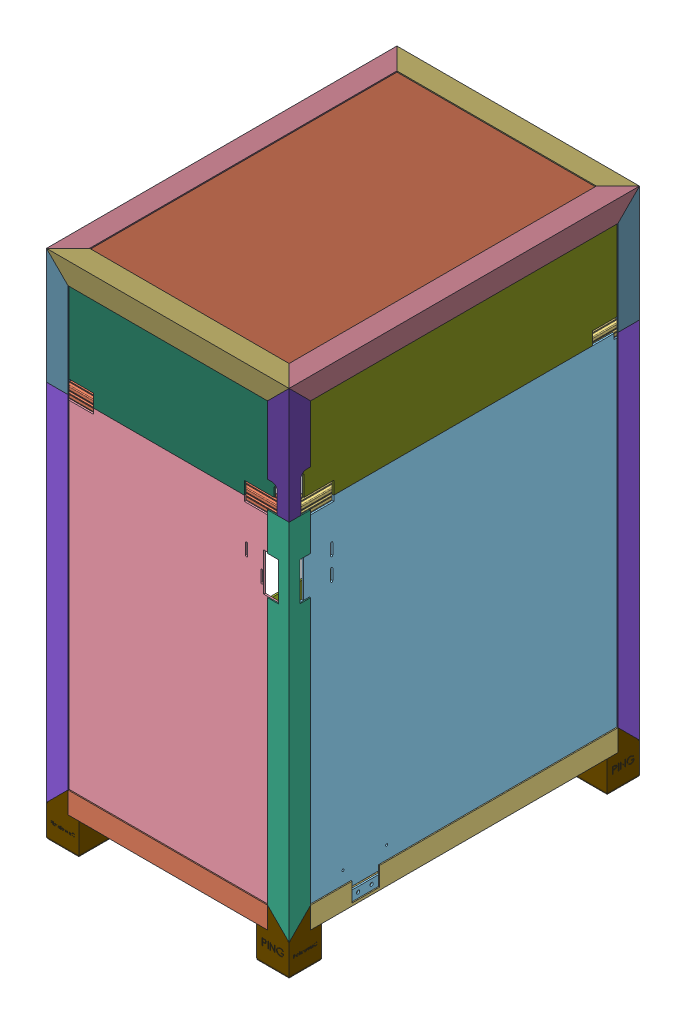
SolidWorks assembly carcasse, configuration Défaut. Lengths in mm.
Overall size (450 950 650).
53 component instances, 24 part files, 67 mates.
Components (placement in the parent):
- cadre-1: cadre [Défaut] at (-215.194 -19.8636 -400) size (440 20 640)
  - Blocks-1: Blocks [Défaut] at (-153.6103 82.5412 1245.1575) x (0 1 0) z (0 0 1) size (20 20 20)
  - Blocks-3: Blocks [Défaut] at (-153.6103 62.5412 625.1575) x (0 0 -1) z (0 1 0) size (20 20 20)
  - Blocks-4: Blocks [Défaut] at (246.3897 82.5412 645.1575) x (0 1 0) z (0 0 -1) size (20 20 20)
  - Blocks-5: Blocks [Défaut] at (246.3897 62.5412 1265.1575) x (0 0 1) z (0 1 0) size (20 20 20)
  - prof_20x20x400mm-1: prof_20x20x400mm [End Finishing_Non-Machined End Finish Options_Type_Single_] at (246.3897 72.5412 635.1575) x (0 0 1) z (-1 0 0) size (20 20 400)
  - prof_20x20x400mm-2: prof_20x20x400mm [End Finishing_Non-Machined End Finish Options_Type_Single_] at (246.3897 72.5412 1255.1575) x (0 0 1) z (-1 0 0) size (20 20 400)
  - prof_20x20x600mm-4: prof_20x20x600mm [End Finishing_Non-Machined End Finish Options_Type_Single_] at (256.3897 72.5412 645.1575) size (20 20 600)
  - prof_20x20x600mm-5: prof_20x20x600mm [End Finishing_Non-Machined End Finish Options_Type_Single_] at (-163.6103 72.5412 645.1575) size (20 20 600)
- prof_20x20x640mm-1: prof_20x20x640mm [End Finishing_Non-Machined End Finish Options_Type_Single_] at (41.1957 42.6776 235.1575) x (1 0 0) z (0 -1 0) size (20 20 640)
- prof_20x20x640mm-2: prof_20x20x640mm [End Finishing_Non-Machined End Finish Options_Type_Single_] at (41.1957 42.6776 855.1575) x (1 0 0) z (0 -1 0) size (20 20 640)
- prof_20x20x640mm-3: prof_20x20x640mm [End Finishing_Non-Machined End Finish Options_Type_Single_] at (-378.8043 42.6776 855.1575) x (1 0 0) z (0 -1 0) size (20 20 640)
- prof_20x20x640mm-4: prof_20x20x640mm [End Finishing_Non-Machined End Finish Options_Type_Single_] at (-378.8043 42.6776 235.1575) x (1 0 0) z (0 -1 0) size (20 20 640)
- cadre-2: cadre [Défaut] at (-122.4146 -534.7812 -400) x (-1 0 0) z (0 0 1) size (440 20 640)
  - Blocks-1: Blocks [Défaut] at (-153.6103 82.5412 1245.1575) x (0 1 0) z (0 0 1) size (20 20 20)
  - Blocks-3: Blocks [Défaut] at (-153.6103 62.5412 625.1575) x (0 0 -1) z (0 1 0) size (20 20 20)
  - Blocks-4: Blocks [Défaut] at (246.3897 82.5412 645.1575) x (0 1 0) z (0 0 -1) size (20 20 20)
  - Blocks-5: Blocks [Défaut] at (246.3897 62.5412 1265.1575) x (0 0 1) z (0 1 0) size (20 20 20)
  - prof_20x20x400mm-1: prof_20x20x400mm [End Finishing_Non-Machined End Finish Options_Type_Single_] at (246.3897 72.5412 635.1575) x (0 0 1) z (-1 0 0) size (20 20 400)
  - prof_20x20x400mm-2: prof_20x20x400mm [End Finishing_Non-Machined End Finish Options_Type_Single_] at (246.3897 72.5412 1255.1575) x (0 0 1) z (-1 0 0) size (20 20 400)
  - prof_20x20x600mm-4: prof_20x20x600mm [End Finishing_Non-Machined End Finish Options_Type_Single_] at (256.3897 72.5412 645.1575) size (20 20 600)
  - prof_20x20x600mm-5: prof_20x20x600mm [End Finishing_Non-Machined End Finish Options_Type_Single_] at (-163.6103 72.5412 645.1575) size (20 20 600)
- plaque_acrylique_680x670-2: plaque_acrylique_680x670 [Défaut] at (51.1957 -282.3224 525.1575) x (0 0 -1) z (1 0 0) size (640 670 3)
- plaque_acrylique_380x670_G-1: plaque_acrylique_380x670_G [Défaut] at (-138.8043 -282.3224 222.1575) size (440 670 3)
- plaque_acrylique_680x670_porte-1: plaque_acrylique_680x670_porte [Défaut] at (-391.8043 -282.3224 525.1575) x (0 0 -1) z (1 0 0) size (640 670 3)
- eclisse_40x40x670_bisote_x1-1: eclisse_40x40x670_bisote_x1 [Défaut] at (-373.8043 -622.3224 240.2711) size (40 675 40)
- eclisse_40x40x670_bisote_x1-2: eclisse_40x40x670_bisote_x1 [Défaut] at (-373.6907 -622.3224 850.1575) x (0 0 -1) z (1 0 0) size (40 675 40)
- eclisse_40x40x670_bisote_x1-4: eclisse_40x40x670_bisote_x1 [Défaut] at (36.0821 -622.3224 240.1575) x (0 0 1) z (-1 0 0) size (40 675 40)
- couvercle-1: couvercle [Défaut] at (191.3923 156.5575 835.9918) size (450 215 650)
  - plaque_acrylique_680x210-2: plaque_acrylique_680x210 [Défaut] at (-583.1966 1.1201 -270.8343) x (0 0 -1) z (1 0 0) size (640 210 3)
  - plaque_acrylique_380x210-2: plaque_acrylique_380x210 [Défaut] at (-330.1966 1.1201 -613.8343) size (440 210 3)
  - plaque_acrylique_380x680-1: plaque_acrylique_380x680 [Défaut] at (-330.1966 106.1201 -270.8343) x (1 0 0) z (0 1 0) size (440 640 3)
  - eclisse_40x40x404_bisote_x2-1: eclisse_40x40x404_bisote_x2 [Défaut] at (-135.1966 91.0065 -595.8343) x (0 0 1) z (0 -1 0) size (40 450 40)
  - eclisse_40x40x704_bisote_x2-1: eclisse_40x40x704_bisote_x2 [Défaut] at (-155.3102 91.1201 -615.8343) x (0 -1 0) z (-1 0 0) size (40 650 40)
  - eclisse_40x40x404_bisote_x2-2: eclisse_40x40x404_bisote_x2 [Défaut] at (-585.1966 91.0065 14.1657) x (0 0 -1) z (0 -1 0) size (40 450 40)
  - eclisse_40x40x704_bisote_x2-2: eclisse_40x40x704_bisote_x2 [Défaut] at (-565.1966 91.0065 -615.8343) x (1 0 0) z (0 -1 0) size (40 650 40)
  - eclisse_40x40x222_bisote_x1-1: eclisse_40x40x222_bisote_x1 [Défaut] at (-565.083 111.1201 -595.8343) x (0 0 1) z (1 0 0) size (40 215 40)
  - eclisse_40x40x222_bisote_x1-2: eclisse_40x40x222_bisote_x1 [Défaut] at (-155.1966 111.1201 -595.7207) x (-1 0 0) z (0 0 1) size (40 215 40)
  - eclisse_40x40x222_bisote_x1-4: eclisse_40x40x222_bisote_x1 [Défaut] at (-565.1966 111.1201 14.052) x (1 0 0) z (0 0 -1) size (40 215 40)
  - plaque_acrylique_380x210_Moteur-1: plaque_acrylique_380x210_Moteur [Défaut] at (-330.1966 1.1201 29.1657) size (440 210 3)
  - plaque_acrylique_680x210_moteur-1: plaque_acrylique_680x210_moteur [Défaut] at (-140.1966 1.1201 -270.8343) x (0 0 -1) z (1 0 0) size (640 210 3)
  - eclisse_40x40x222_bisote_x1_Moteur-1: eclisse_40x40x222_bisote_x1_Moteur [Défaut] at (-155.3102 111.1201 14.1657) x (0 0 -1) z (-1 0 0) size (40 215 40)
- Pied-1: Pied [Défaut] at (-3.8043 -622.3224 280.1575) x (-1 0 0) z (0 -1 0) size (60 60 100)
- Pied-2: Pied [Défaut] at (-3.8043 -622.3224 810.1575) x (0 0 -1) z (0 -1 0) size (60 60 100)
- Pied-3: Pied [Défaut] at (-333.8043 -622.3224 810.1575) x (1 0 0) z (0 -1 0) size (60 60 100)
- Pied-4: Pied [Défaut] at (-333.8043 -622.3224 280.1575) x (0 0 1) z (0 -1 0) size (60 60 100)
- eclisse_bas_40x40x704-2: eclisse_bas_40x40x704 [Défaut] at (-373.8043 -602.2087 830.1575) x (1 0 0) z (0 1 0) size (40 570 40)
- eclisse_bas_40x40x404-1: eclisse_bas_40x40x404 [Défaut] at (-353.8043 -602.2087 240.1575) x (0 0 1) z (0 1 0) size (40 370 40)
- eclisse_bas_40x40x404-2: eclisse_bas_40x40x404 [Défaut] at (16.1957 -602.2087 850.1575) x (0 0 -1) z (0 1 0) size (40 370 40)
- eclisse_bas_support_Z_40x40x704-1: eclisse_bas_support_Z_40x40x704 [Défaut] at (36.0821 -602.3224 830.1575) x (0 1 0) z (-1 0 0) size (40 570 40)
- plaque_acrylique_380x670_D-2: plaque_acrylique_380x670_D [Défaut] at (-198.8043 -282.3224 868.1575) x (-1 0 0) z (0 0 -1) size (440 670 3)
- plaque_acrylique_bas_380x680-1: plaque_acrylique_bas_380x680 [Défaut] at (-138.8043 -620.3224 565.1575) x (1 0 0) z (0 1 0) size (440 640 3)
- eclisse_40x40x670_bisote_x1-Moteur-1: eclisse_40x40x670_bisote_x1-Moteur [Défaut] at (36.1957 -622.3224 850.0438) x (-1 0 0) z (0 0 -1) size (40 675 40)
Mates (geometry in assembly coordinates):
- Coïncidente66: coincident anti-aligned: plane of plaque_acrylique_680x670_porte-1 through (-391.8043 -282.3224 525.1575) normal (-1 0 0); plane of eclisse_40x40x670_bisote_x1-1 through (-391.8043 52.6776 222.1575) normal (1 0 0)
- Coïncidente67: coincident aligned: plane of plaque_acrylique_680x670_porte-1 through (-388.8043 52.6776 865.1575) normal (0 1 0); plane of eclisse_40x40x670_bisote_x1-1 through (-373.8043 52.6776 240.2711) normal (0 1 0)
- Coïncidente68: coincident anti-aligned: plane of plaque_acrylique_680x670-2 through (54.1957 -282.3224 525.1575) normal (1 0 0); plane of eclisse_40x40x670_bisote_x1-4 through (54.1957 52.6776 222.1575) normal (-1 0 0)
- Coïncidente72: coincident anti-aligned: plane of plaque_acrylique_680x670_porte-1 through (-391.8043 -282.3224 525.1575) normal (-1 0 0); plane of eclisse_40x40x670_bisote_x1-2 through (-391.8043 52.6776 868.1575) normal (1 0 0)
- Coïncidente100: coincident: plane of plaque_acrylique_680x670_porte-1 through (-388.8043 52.6776 865.1575) normal (0 1 0); line of eclisse_40x40x670_bisote_x1-2 through (-391.8043 52.6776 868.1575) axis (0 0 -1)
- Coïncidente130: coincident anti-aligned: plane of eclisse_40x40x670_bisote_x1-2 through (196.1957 -622.3224 870.1575) normal (0 -0.707107 -0.707107); plane of Pied-3 through (-391.8043 -582.3224 830.1575) normal (0 0.707107 0.707107)
- Coïncidente132: coincident anti-aligned: plane of plaque_acrylique_680x670_porte-1 through (-391.8043 -282.3224 525.1575) normal (-1 0 0); plane of eclisse_bas_40x40x704-2 through (-391.8043 -620.3224 260.1575) normal (1 0 0)
- Coïncidente134: coincident anti-aligned: line of eclisse_40x40x670_bisote_x1-2 through (-393.8043 52.6776 830.1575) axis (0 -1 0); line of eclisse_bas_40x40x704-2 through (-393.8043 -622.3224 830.1575) axis (0 1 0)
- Coïncidente140: coincident anti-aligned: line of Pied-3 through (-353.8043 -582.3224 870.1575) axis (0 -1 0); line of eclisse_bas_40x40x404-2 through (-353.8043 -622.3224 870.1575) axis (0 1 0)
- Coïncidente142: coincident anti-aligned: plane of plaque_acrylique_680x670-2 through (54.1957 -282.3224 525.1575) normal (1 0 0); plane of eclisse_bas_support_Z_40x40x704-1 through (54.1957 -620.3224 260.1575) normal (-1 0 0)
- Coïncidente144: coincident anti-aligned: plane of Pied-2 through (54.1957 -582.3224 830.1575) normal (0 0 -1); plane of eclisse_bas_support_Z_40x40x704-1 through (36.0821 -602.3224 830.1575) normal (0 0 1)
- Coïncidente156: coincident anti-aligned: plane of eclisse_bas_40x40x404-2 through (-353.8043 -620.3224 868.1575) normal (0 0 -1); plane of plaque_acrylique_380x670_D-2 through (-198.8043 -282.3224 868.1575) normal (0 0 1)
- Coïncidente157: coincident anti-aligned: plane of eclisse_40x40x670_bisote_x1-2 through (-391.8043 52.6776 868.1575) normal (0 0 -1); plane of plaque_acrylique_380x670_D-2 through (-198.8043 -282.3224 868.1575) normal (0 0 1)
- Coïncidente163: coincident anti-aligned: plane of cadre-1/Blocks-1 through (-388.8043 42.6776 865.1575) normal (0 -1 0); plane of prof_20x20x640mm-3 through (-387.3043 42.6776 863.6575) normal (0 1 0)
- Coïncidente164: coincident aligned: plane of cadre-1/Blocks-1 through (-388.8043 42.6776 865.1575) normal (-1 0 0); plane of prof_20x20x640mm-3 through (-388.8043 -597.3224 858.9075) normal (-1 0 0)
- Coïncidente165: coincident aligned: plane of cadre-1/Blocks-1 through (-368.8043 62.6776 865.1575) normal (0 0 1); plane of prof_20x20x640mm-3 through (-382.5543 -597.3224 865.1575) normal (0 0 1)
- Coïncidente166: coincident anti-aligned: plane of prof_20x20x640mm-3 through (-387.3043 -597.3224 863.6575) normal (0 -1 0); plane of cadre-2/Blocks-5 through (-368.8043 -597.3224 865.1575) normal (0 1 0)
- Coïncidente167: coincident aligned: plane of prof_20x20x640mm-3 through (-382.5543 -597.3224 865.1575) normal (0 0 1); plane of cadre-2/Blocks-5 through (-388.8043 -617.3224 865.1575) normal (0 0 1)
- Coïncidente168: coincident aligned: plane of prof_20x20x640mm-3 through (-388.8043 -597.3224 858.9075) normal (-1 0 0); plane of cadre-2/Blocks-5 through (-388.8043 -617.3224 845.1575) normal (-1 0 0)
- Coïncidente169: coincident anti-aligned: plane of prof_20x20x640mm-2 through (32.6957 -597.3224 863.6575) normal (0 -1 0); plane of cadre-2/Blocks-1 through (51.1957 -597.3224 865.1575) normal (0 1 0)
- Coïncidente170: coincident aligned: plane of prof_20x20x640mm-2 through (37.4457 -597.3224 865.1575) normal (0 0 1); plane of cadre-2/Blocks-1 through (31.1957 -617.3224 865.1575) normal (0 0 1)
- Coïncidente171: coincident aligned: plane of prof_20x20x640mm-2 through (51.1957 -597.3224 858.9075) normal (1 0 0); plane of cadre-2/Blocks-1 through (51.1957 -597.3224 865.1575) normal (1 0 0)
- Coïncidente172: coincident anti-aligned: plane of prof_20x20x640mm-1 through (32.6957 -597.3224 243.6575) normal (0 -1 0); plane of cadre-2/Blocks-3 through (31.1957 -597.3224 225.1575) normal (0 1 0)
- Coïncidente173: coincident aligned: plane of prof_20x20x640mm-1 through (51.1957 -597.3224 238.9075) normal (1 0 0); plane of cadre-2/Blocks-3 through (51.1957 -617.3224 245.1575) normal (1 0 0)
- Coïncidente174: coincident aligned: plane of prof_20x20x640mm-1 through (44.9457 -597.3224 225.1575) normal (0 0 -1); plane of cadre-2/Blocks-3 through (51.1957 -617.3224 225.1575) normal (0 0 -1)
- Coïncidente175: coincident aligned: plane of cadre-1/Blocks-3 through (-388.8043 62.6776 245.1575) normal (-1 0 0); plane of prof_20x20x640mm-4 through (-388.8043 -597.3224 231.4075) normal (-1 0 0)
- Coïncidente176: coincident aligned: plane of cadre-1/Blocks-3 through (-388.8043 62.6776 225.1575) normal (0 0 -1); plane of prof_20x20x640mm-4 through (-382.5543 -597.3224 225.1575) normal (0 0 -1)
- Coïncidente177: coincident anti-aligned: plane of cadre-1/Blocks-3 through (-368.8043 42.6776 225.1575) normal (0 -1 0); plane of prof_20x20x640mm-4 through (-387.3043 42.6776 243.6575) normal (0 1 0)
- Coïncidente183: coincident aligned: plane of prof_20x20x640mm-2 through (51.1957 -597.3224 858.9075) normal (1 0 0); plane of plaque_acrylique_380x670_D-2 through (51.1957 52.6776 865.1575) normal (1 0 0)
- Coïncidente186: coincident aligned: plane of cadre-1/prof_20x20x400mm-2 through (-368.8043 56.4276 865.1575) normal (0 0 1); plane of plaque_acrylique_680x670-2 through (54.1957 52.6776 865.1575) normal (0 0 1)
- Coïncidente187: coincident aligned: plane of cadre-1/prof_20x20x400mm-1 through (-368.8043 48.9276 225.1575) normal (0 0 -1); plane of plaque_acrylique_680x670_porte-1 through (-388.8043 52.6776 225.1575) normal (0 0 -1)
- Coïncidente191: coincident anti-aligned: plane of cadre-2/prof_20x20x400mm-1 through (31.1957 -617.3224 238.9075) normal (0 -1 0); plane of plaque_acrylique_bas_380x680-1 through (-138.8043 -617.3224 565.1575) normal (0 1 0)
- Coïncidente192: coincident aligned: plane of cadre-2/prof_20x20x400mm-2 through (31.1957 -611.0724 865.1575) normal (0 0 1); plane of plaque_acrylique_bas_380x680-1 through (-388.8043 -617.3224 865.1575) normal (0 0 1)
- Coïncidente199: coincident anti-aligned: line of eclisse_40x40x670_bisote_x1-4 through (56.1957 -622.3224 220.1575) axis (0 0.707107 0.707107); line of Pied-1 through (56.1957 -582.3224 260.1575) axis (0 -0.707107 -0.707107)
- Coïncidente201: coincident anti-aligned: plane of plaque_acrylique_680x670-2 through (54.1957 -282.3224 525.1575) normal (1 0 0); plane of Pied-2 through (54.1957 -582.3224 868.1575) normal (-1 0 0)
- Coïncidente204: coincident anti-aligned: plane of prof_20x20x640mm-1 through (44.9457 -597.3224 225.1575) normal (0 0 -1); plane of plaque_acrylique_380x670_G-1 through (-138.8043 -282.3224 225.1575) normal (0 0 1)
- Coïncidente205: coincident aligned: plane of cadre-2/prof_20x20x400mm-1 through (31.1957 -617.3224 231.4075) normal (0 -1 0); plane of plaque_acrylique_380x670_G-1 through (-388.8043 -617.3224 225.1575) normal (0 -1 0)
- Coïncidente206: coincident aligned: plane of prof_20x20x640mm-1 through (51.1957 -597.3224 231.4075) normal (1 0 0); plane of plaque_acrylique_380x670_G-1 through (51.1957 52.6776 225.1575) normal (1 0 0)
- Coïncidente207: coincident anti-aligned: plane of prof_20x20x640mm-4 through (-388.8043 -597.3224 231.4075) normal (-1 0 0); plane of plaque_acrylique_680x670_porte-1 through (-388.8043 -282.3224 525.1575) normal (1 0 0)
- Coïncidente208: coincident anti-aligned: plane of plaque_acrylique_380x670_G-1 through (-138.8043 -282.3224 222.1575) normal (0 0 -1); plane of eclisse_40x40x670_bisote_x1-1 through (-391.8043 52.6776 222.1575) normal (0 0 1)
- Coïncidente210: coincident anti-aligned: plane of plaque_acrylique_380x670_G-1 through (-138.8043 -282.3224 222.1575) normal (0 0 -1); plane of eclisse_40x40x670_bisote_x1-4 through (54.1957 52.6776 222.1575) normal (0 0 1)
- Parallèle4: parallel anti-aligned: line of eclisse_40x40x670_bisote_x1-1 through (-393.8043 -622.3224 220.1575) axis (0.707107 0.707107 0); line of Pied-4 through (-353.8043 -582.3224 220.1575) axis (-0.707107 -0.707107 0)
- Coïncidente218: coincident: plane of cadre-2/prof_20x20x400mm-2 through (31.1957 -617.3224 858.9075) normal (0 -1 0); line of plaque_acrylique_380x670_D-2 through (51.1957 -617.3224 868.1575) axis (-1 0 0)
- Coïncidente223: coincident anti-aligned: plane of eclisse_bas_support_Z_40x40x704-1 through (54.1957 -620.3224 260.1575) normal (0 1 0); plane of plaque_acrylique_bas_380x680-1 through (-138.8043 -620.3224 565.1575) normal (0 -1 0)
- Coïncidente224: coincident anti-aligned: plane of eclisse_bas_40x40x704-2 through (-391.8043 -620.3224 260.1575) normal (0 1 0); plane of plaque_acrylique_bas_380x680-1 through (-138.8043 -620.3224 565.1575) normal (0 -1 0)
- Coïncidente225: coincident anti-aligned: plane of plaque_acrylique_380x670_G-1 through (-138.8043 -282.3224 222.1575) normal (0 0 -1); plane of eclisse_bas_40x40x404-1 through (16.1957 -620.3224 222.1575) normal (0 0 1)
- Coïncidente226: coincident anti-aligned: plane of eclisse_bas_40x40x404-1 through (16.1957 -620.3224 222.1575) normal (0 1 0); plane of plaque_acrylique_bas_380x680-1 through (-138.8043 -620.3224 565.1575) normal (0 -1 0)
- Coïncidente227: coincident anti-aligned: plane of Pied-1 through (16.1957 -582.3224 222.1575) normal (-1 0 0); plane of eclisse_bas_40x40x404-1 through (16.1957 -602.2087 240.1575) normal (1 0 0)
- Coïncidente228: coincident anti-aligned: plane of plaque_acrylique_680x670_porte-1 through (-391.8043 -282.3224 525.1575) normal (-1 0 0); plane of Pied-3 through (-391.8043 -582.3224 830.1575) normal (1 0 0)
- Coïncidente229: coincident anti-aligned: plane of plaque_acrylique_380x670_G-1 through (-138.8043 -282.3224 222.1575) normal (0 0 -1); plane of Pied-4 through (-353.8043 -582.3224 222.1575) normal (0 0 1)
- Coïncidente230: coincident anti-aligned: plane of plaque_acrylique_680x670_porte-1 through (-391.8043 -282.3224 525.1575) normal (-1 0 0); plane of Pied-4 through (-391.8043 -582.3224 222.1575) normal (1 0 0)
- Coïncidente231: coincident anti-aligned: plane of plaque_acrylique_380x670_G-1 through (-138.8043 -282.3224 222.1575) normal (0 0 -1); plane of Pied-1 through (54.1957 -582.3224 222.1575) normal (0 0 1)
- Coïncidente232: coincident aligned: plane of plaque_acrylique_380x670_G-1 through (-138.8043 -282.3224 222.1575) normal (0 0 -1); plane of couvercle-1/plaque_acrylique_380x210-2 through (-138.8043 157.6776 222.1575) normal (0 0 -1)
- Coïncidente233: coincident aligned: plane of couvercle-1/plaque_acrylique_380x210_Moteur-1 through (-138.8043 157.6776 868.1575) normal (0 0 1); plane of plaque_acrylique_380x670_D-2 through (-198.8043 -282.3224 868.1575) normal (0 0 1)
- Coïncidente234: coincident anti-aligned: line of plaque_acrylique_680x670-2 through (54.1957 52.6776 265.1575) axis (0 0 1); line of couvercle-1/plaque_acrylique_680x210_moteur-1 through (54.1957 52.6776 785.1575) axis (0 0 -1)
- Coïncidente235: coincident aligned: plane of plaque_acrylique_680x670-2 through (54.1957 -282.3224 525.1575) normal (1 0 0); plane of couvercle-1/plaque_acrylique_680x210_moteur-1 through (54.1957 157.6776 565.1575) normal (1 0 0)
- Coïncidente236: coincident anti-aligned: plane of plaque_acrylique_680x670-2 through (54.1957 -282.3224 525.1575) normal (1 0 0); plane of eclisse_40x40x670_bisote_x1-Moteur-1 through (54.1957 52.6776 868.1575) normal (-1 0 0)
- Coïncidente237: coincident anti-aligned: plane of plaque_acrylique_380x670_D-2 through (-198.8043 -282.3224 868.1575) normal (0 0 1); plane of eclisse_40x40x670_bisote_x1-Moteur-1 through (54.1957 52.6776 868.1575) normal (0 0 -1)
- Coïncidente238: coincident anti-aligned: line of Pied-2 through (16.1957 -582.3224 870.1575) axis (0.707107 -0.707107 0); line of eclisse_40x40x670_bisote_x1-Moteur-1 through (56.1957 -622.3224 870.1575) axis (-0.707107 0.707107 0)
- Coïncidente239: coincident anti-aligned: plane of plaque_acrylique_680x670_porte-1 through (-388.8043 -282.3224 525.1575) normal (1 0 0); plane of plaque_acrylique_bas_380x680-1 through (-388.8043 -617.3224 225.1575) normal (-1 0 0)
- Coïncidente240: coincident anti-aligned: plane of cadre-2/prof_20x20x600mm-5 through (51.1957 -611.0724 845.1575) normal (1 0 0); plane of plaque_acrylique_680x670-2 through (51.1957 -282.3224 525.1575) normal (-1 0 0)
- Coïncidente241: coincident aligned: plane of cadre-2/prof_20x20x600mm-5 through (44.9457 -617.3224 845.1575) normal (0 -1 0); plane of plaque_acrylique_680x670-2 through (54.1957 -617.3224 865.1575) normal (0 -1 0)
- Coïncidente242: coincident aligned: plane of cadre-2/prof_20x20x600mm-4 through (-382.5543 -617.3224 845.1575) normal (0 -1 0); plane of plaque_acrylique_680x670_porte-1 through (-388.8043 -617.3224 865.1575) normal (0 -1 0)
- Coïncidente243: coincident anti-aligned: plane of eclisse_bas_40x40x404-2 through (-353.8043 -620.3224 868.1575) normal (0 1 0); plane of plaque_acrylique_bas_380x680-1 through (-138.8043 -620.3224 565.1575) normal (0 -1 0)
- Coïncidente244: coincident anti-aligned: plane of Pied-2 through (-3.8043 -622.3224 810.1575) normal (0 1 0); plane of eclisse_bas_40x40x404-2 through (-353.8043 -622.3224 870.1575) normal (0 -1 0)
- Coïncidente245: coincident anti-aligned: plane of Pied-4 through (-333.8043 -622.3224 280.1575) normal (0 1 0); plane of eclisse_bas_40x40x704-2 through (-393.8043 -622.3224 260.1575) normal (0 -1 0)
- Coïncidente246: coincident anti-aligned: plane of Pied-1 through (-3.8043 -622.3224 280.1575) normal (0 1 0); plane of eclisse_bas_40x40x404-1 through (16.1957 -622.3224 220.1575) normal (0 -1 0)
